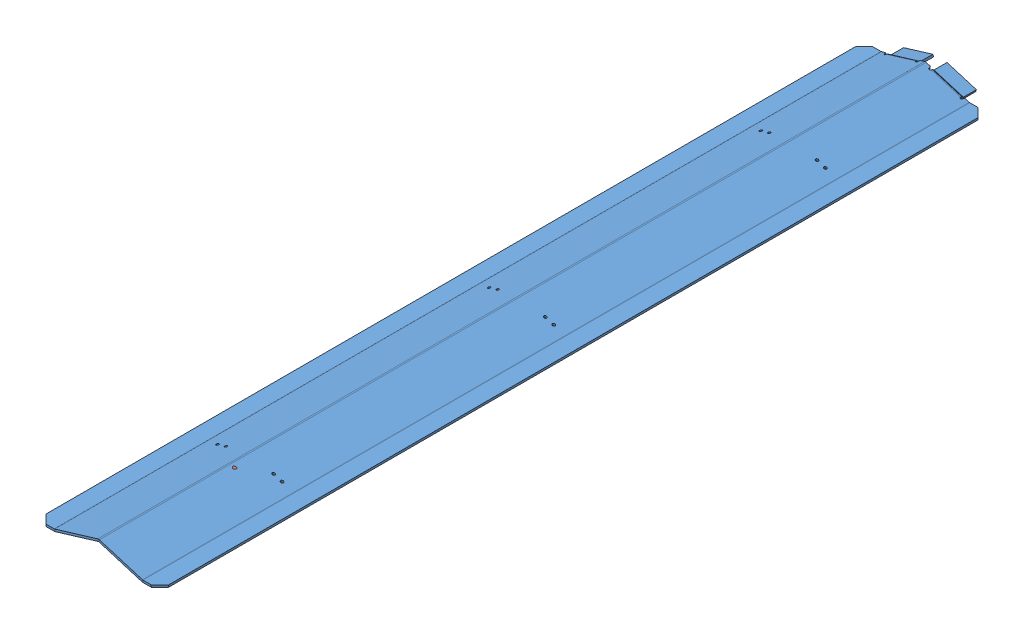
SolidWorks assembly GE-19223, configuration Default. Lengths in mm.
Overall size (177.8 22.23 1219.2).
2 component instances, 2 part files, 0 mates.
Components (placement in the parent):
- GE-19223-1-1: GE-19223-1 [Default] at origin size (177.8 22.23 1219.2)
- PEM-FH-832-6ZI-1: PEM-FH-832-6ZI [Default] at (7.1934 20.2237 419.1) x (-0.289806 -0.957086 0) z (-0.571052 0.172915 0.802496) size (9.53 6.02 6.02)
